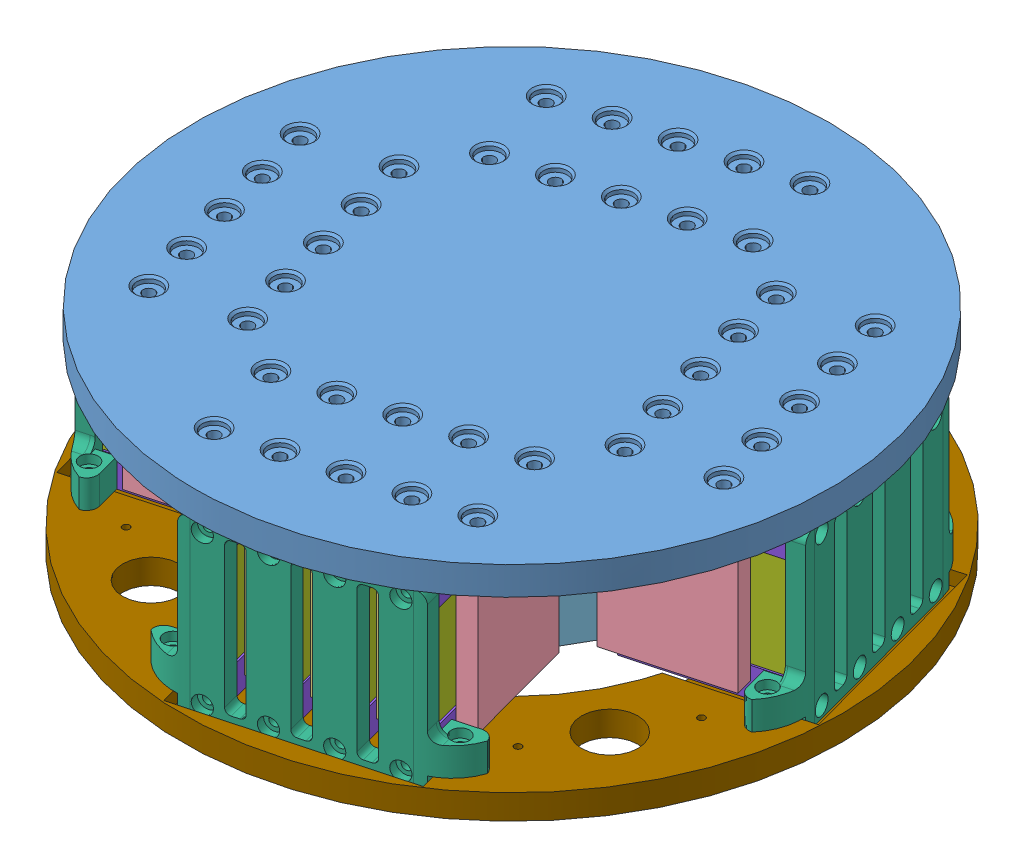
SolidWorks assembly Top_Plate_and_Dampener, configuration Default. Lengths in mm.
Overall size (255.23 60.54 255.23).
80 component instances, 9 part files, 20 mates.
Components (placement in the parent):
- Top_Plate_Test-2: Top_Plate_Test [Default] at (162.7296 -127.7331 -67.6253) size (180 8 180)
- ES-50 supp-2: ES-50 supp [默认] at (103.6666 -172.7331 -107.1936) x (0.965248 0 -0.261336) z (0.261336 0 0.965248) size (75.73 45 71)
- Fin_Long-1: Fin_Long [Default] at (30.3895 -152.9924 -80.4761) x (0 -1 0) z (0.965248 0 -0.261336) size (41.91 5.08 38.1)
- Fin_Long-2: Fin_Long [Default] at (34.3723 -152.9924 -65.7657) x (0 -1 0) z (0.965248 0 -0.261336) size (41.91 5.08 38.1)
- Fin_Long-3: Fin_Long [Default] at (26.4068 -152.9924 -95.1865) x (0 -1 0) z (0.965248 0 -0.261336) size (41.91 5.08 38.1)
- Fin_Short-1: Fin_Short [Default] at (48.3509 -135.5242 -53.7617) x (-0.965248 0 0.261336) z (0 -1 0) size (32.51 5.08 41.91)
- Fin_Long-4: Fin_Long [Default] at (73.9152 -152.9924 -163.5373) x (0 -1 0) z (0.261336 0 0.965248) size (41.91 5.08 38.1)
- Fin_Long-5: Fin_Long [Default] at (156.9764 -152.9924 -120.0117) x (0 -1 0) z (-0.965248 0 0.261336) size (41.91 5.08 38.1)
- Fin_Long-6: Fin_Long [Default] at (113.4508 -152.9924 -36.9505) x (0 -1 0) z (-0.261336 0 -0.965248) size (41.91 5.08 38.1)
- Fin_Long-7: Fin_Long [Default] at (59.2048 -152.9924 -159.5546) x (0 -1 0) z (0.261336 0 0.965248) size (41.91 5.08 38.1)
- Fin_Long-8: Fin_Long [Default] at (152.9937 -152.9924 -134.7221) x (0 -1 0) z (-0.965248 0 0.261336) size (41.91 5.08 38.1)
- Fin_Long-9: Fin_Long [Default] at (128.1612 -152.9924 -40.9332) x (0 -1 0) z (-0.261336 0 -0.965248) size (41.91 5.08 38.1)
- Fin_Long-10: Fin_Long [Default] at (88.6255 -152.9924 -167.5201) x (0 -1 0) z (0.261336 0 0.965248) size (41.91 5.08 38.1)
- Fin_Long-11: Fin_Long [Default] at (160.9592 -152.9924 -105.3013) x (0 -1 0) z (-0.965248 0 0.261336) size (41.91 5.08 38.1)
- Fin_Long-12: Fin_Long [Default] at (98.7404 -152.9924 -32.9677) x (0 -1 0) z (-0.261336 0 -0.965248) size (41.91 5.08 38.1)
- Fin_Short-2: Fin_Short [Default] at (32.4199 -135.5242 -112.6032) x (-0.965248 0 0.261336) z (0 -1 0) size (32.51 5.08 41.91)
- Fin_Short-3: Fin_Short [Default] at (106.0423 -135.5242 -161.507) x (-0.261336 0 -0.965248) z (0 -1 0) size (32.51 5.08 41.91)
- Fin_Short-4: Fin_Short [Default] at (154.946 -135.5242 -87.8846) x (0.965248 0 -0.261336) z (0 -1 0) size (32.51 5.08 41.91)
- Fin_Short-5: Fin_Short [Default] at (81.3237 -135.5242 -38.9808) x (0.261336 0 0.965248) z (0 -1 0) size (32.51 5.08 41.91)
- Fin_Short-6: Fin_Short [Default] at (47.2007 -135.5242 -145.576) x (-0.261336 0 -0.965248) z (0 -1 0) size (32.51 5.08 41.91)
- Fin_Short-7: Fin_Short [Default] at (139.015 -135.5242 -146.7261) x (0.965248 0 -0.261336) z (0 -1 0) size (32.51 5.08 41.91)
- Fin_Short-8: Fin_Short [Default] at (140.1652 -135.5242 -54.9118) x (0.261336 0 0.965248) z (0 -1 0) size (32.51 5.08 41.91)
- Rectangular_Weight-1: Rectangular_Weight [Default] at (112.6132 -169.6431 -99.3448) x (0.261336 0 0.965248) z (-0.965248 0 0.261336) size (75 41.91 75)
- VerticalBraceMagnets-1: VerticalBraceMagnets [Default] at (72.0026 -36.9043 136.8574) x (0.261336 0 0.965248) z (0 -1 0) size (77.76 45.19 49)
  - MagnetBracket_draft4_20160427-1: MagnetBracket_draft4_20160427 [Default] at (-252.0457 -3.1326 136.3687) size (77.76 10 49)
  - BraceMagVertSolid_draft6_20160427-2: BraceMagVertSolid_draft6_20160427 [Default] at (-186.916 -115.49 293.8662) x (0 0 1) z (0 1 0) size (45.4 6.82 42.19)
    - MagnetActual_draf6_20160424-1: MagnetActual_draf6_20160424 [Default] at (-195.3725 -16.2397 114.3575) size (34.75 5.82 40.19)
    - VertMagBraceSolid_draft3_20160427-1: VertMagBraceSolid_draft3_20160427 [Default] at (-155.2965 -9.9197 112.0675) x (0 0 -1) z (0 1 0) size (39.9 45.4 6.82)
  - BraceMagVertSolid_draft6_20160427-3: BraceMagVertSolid_draft6_20160427 [Default] at (-202.216 -115.49 293.8662) x (0 0 1) z (0 1 0) size (45.4 6.82 42.19)
    - MagnetActual_draf6_20160424-1: MagnetActual_draf6_20160424 [Default] at (-195.3725 -16.2397 114.3575) size (34.75 5.82 40.19)
    - VertMagBraceSolid_draft3_20160427-1: VertMagBraceSolid_draft3_20160427 [Default] at (-155.2965 -9.9197 112.0675) x (0 0 -1) z (0 1 0) size (39.9 45.4 6.82)
  - BraceMagVertSolid_draft6_20160427-4: BraceMagVertSolid_draft6_20160427 [Default] at (-217.516 -115.49 293.8662) x (0 0 1) z (0 1 0) size (45.4 6.82 42.19)
    - MagnetActual_draf6_20160424-1: MagnetActual_draf6_20160424 [Default] at (-195.3725 -16.2397 114.3575) size (34.75 5.82 40.19)
    - VertMagBraceSolid_draft3_20160427-1: VertMagBraceSolid_draft3_20160427 [Default] at (-155.2965 -9.9197 112.0675) x (0 0 -1) z (0 1 0) size (39.9 45.4 6.82)
  - BraceMagVertSolid_draft6_20160427-5: BraceMagVertSolid_draft6_20160427 [Default] at (-232.816 -115.49 293.8662) x (0 0 1) z (0 1 0) size (45.4 6.82 42.19)
    - MagnetActual_draf6_20160424-1: MagnetActual_draf6_20160424 [Default] at (-195.3725 -16.2397 114.3575) size (34.75 5.82 40.19)
    - VertMagBraceSolid_draft3_20160427-1: VertMagBraceSolid_draft3_20160427 [Default] at (-155.2965 -9.9197 112.0675) x (0 0 -1) z (0 1 0) size (39.9 45.4 6.82)
- VerticalBraceMagnets-2: VerticalBraceMagnets [Default] at (-143.4184 -36.9043 -121.9243) x (-0.965248 0 0.261336) z (0 -1 0) size (77.76 45.19 49)
  - MagnetBracket_draft4_20160427-1: MagnetBracket_draft4_20160427 [Default] at (-252.0457 -3.1326 136.3687) size (77.76 10 49)
  - BraceMagVertSolid_draft6_20160427-2: BraceMagVertSolid_draft6_20160427 [Default] at (-186.916 -115.49 293.8662) x (0 0 1) z (0 1 0) size (45.4 6.82 42.19)
    - MagnetActual_draf6_20160424-1: MagnetActual_draf6_20160424 [Default] at (-195.3725 -16.2397 114.3575) size (34.75 5.82 40.19)
    - VertMagBraceSolid_draft3_20160427-1: VertMagBraceSolid_draft3_20160427 [Default] at (-155.2965 -9.9197 112.0675) x (0 0 -1) z (0 1 0) size (39.9 45.4 6.82)
  - BraceMagVertSolid_draft6_20160427-3: BraceMagVertSolid_draft6_20160427 [Default] at (-202.216 -115.49 293.8662) x (0 0 1) z (0 1 0) size (45.4 6.82 42.19)
    - MagnetActual_draf6_20160424-1: MagnetActual_draf6_20160424 [Default] at (-195.3725 -16.2397 114.3575) size (34.75 5.82 40.19)
    - VertMagBraceSolid_draft3_20160427-1: VertMagBraceSolid_draft3_20160427 [Default] at (-155.2965 -9.9197 112.0675) x (0 0 -1) z (0 1 0) size (39.9 45.4 6.82)
  - BraceMagVertSolid_draft6_20160427-4: BraceMagVertSolid_draft6_20160427 [Default] at (-217.516 -115.49 293.8662) x (0 0 1) z (0 1 0) size (45.4 6.82 42.19)
    - MagnetActual_draf6_20160424-1: MagnetActual_draf6_20160424 [Default] at (-195.3725 -16.2397 114.3575) size (34.75 5.82 40.19)
    - VertMagBraceSolid_draft3_20160427-1: VertMagBraceSolid_draft3_20160427 [Default] at (-155.2965 -9.9197 112.0675) x (0 0 -1) z (0 1 0) size (39.9 45.4 6.82)
  - BraceMagVertSolid_draft6_20160427-5: BraceMagVertSolid_draft6_20160427 [Default] at (-232.816 -115.49 293.8662) x (0 0 1) z (0 1 0) size (45.4 6.82 42.19)
    - MagnetActual_draf6_20160424-1: MagnetActual_draf6_20160424 [Default] at (-195.3725 -16.2397 114.3575) size (34.75 5.82 40.19)
    - VertMagBraceSolid_draft3_20160427-1: VertMagBraceSolid_draft3_20160427 [Default] at (-155.2965 -9.9197 112.0675) x (0 0 -1) z (0 1 0) size (39.9 45.4 6.82)
- VerticalBraceMagnets-3: VerticalBraceMagnets [Default] at (115.3634 -36.9043 -337.3452) x (-0.261336 0 -0.965248) z (0 -1 0) size (77.76 45.19 49)
  - MagnetBracket_draft4_20160427-1: MagnetBracket_draft4_20160427 [Default] at (-252.0457 -3.1326 136.3687) size (77.76 10 49)
  - BraceMagVertSolid_draft6_20160427-2: BraceMagVertSolid_draft6_20160427 [Default] at (-186.916 -115.49 293.8662) x (0 0 1) z (0 1 0) size (45.4 6.82 42.19)
    - MagnetActual_draf6_20160424-1: MagnetActual_draf6_20160424 [Default] at (-195.3725 -16.2397 114.3575) size (34.75 5.82 40.19)
    - VertMagBraceSolid_draft3_20160427-1: VertMagBraceSolid_draft3_20160427 [Default] at (-155.2965 -9.9197 112.0675) x (0 0 -1) z (0 1 0) size (39.9 45.4 6.82)
  - BraceMagVertSolid_draft6_20160427-3: BraceMagVertSolid_draft6_20160427 [Default] at (-202.216 -115.49 293.8662) x (0 0 1) z (0 1 0) size (45.4 6.82 42.19)
    - MagnetActual_draf6_20160424-1: MagnetActual_draf6_20160424 [Default] at (-195.3725 -16.2397 114.3575) size (34.75 5.82 40.19)
    - VertMagBraceSolid_draft3_20160427-1: VertMagBraceSolid_draft3_20160427 [Default] at (-155.2965 -9.9197 112.0675) x (0 0 -1) z (0 1 0) size (39.9 45.4 6.82)
  - BraceMagVertSolid_draft6_20160427-4: BraceMagVertSolid_draft6_20160427 [Default] at (-217.516 -115.49 293.8662) x (0 0 1) z (0 1 0) size (45.4 6.82 42.19)
    - MagnetActual_draf6_20160424-1: MagnetActual_draf6_20160424 [Default] at (-195.3725 -16.2397 114.3575) size (34.75 5.82 40.19)
    - VertMagBraceSolid_draft3_20160427-1: VertMagBraceSolid_draft3_20160427 [Default] at (-155.2965 -9.9197 112.0675) x (0 0 -1) z (0 1 0) size (39.9 45.4 6.82)
  - BraceMagVertSolid_draft6_20160427-5: BraceMagVertSolid_draft6_20160427 [Default] at (-232.816 -115.49 293.8662) x (0 0 1) z (0 1 0) size (45.4 6.82 42.19)
    - MagnetActual_draf6_20160424-1: MagnetActual_draf6_20160424 [Default] at (-195.3725 -16.2397 114.3575) size (34.75 5.82 40.19)
    - VertMagBraceSolid_draft3_20160427-1: VertMagBraceSolid_draft3_20160427 [Default] at (-155.2965 -9.9197 112.0675) x (0 0 -1) z (0 1 0) size (39.9 45.4 6.82)
- VerticalBraceMagnets-4: VerticalBraceMagnets [Default] at (330.7843 -36.9043 -78.5635) x (0.965248 0 -0.261336) z (0 -1 0) size (77.76 45.19 49)
  - MagnetBracket_draft4_20160427-1: MagnetBracket_draft4_20160427 [Default] at (-252.0457 -3.1326 136.3687) size (77.76 10 49)
  - BraceMagVertSolid_draft6_20160427-2: BraceMagVertSolid_draft6_20160427 [Default] at (-186.916 -115.49 293.8662) x (0 0 1) z (0 1 0) size (45.4 6.82 42.19)
    - MagnetActual_draf6_20160424-1: MagnetActual_draf6_20160424 [Default] at (-195.3725 -16.2397 114.3575) size (34.75 5.82 40.19)
    - VertMagBraceSolid_draft3_20160427-1: VertMagBraceSolid_draft3_20160427 [Default] at (-155.2965 -9.9197 112.0675) x (0 0 -1) z (0 1 0) size (39.9 45.4 6.82)
  - BraceMagVertSolid_draft6_20160427-3: BraceMagVertSolid_draft6_20160427 [Default] at (-202.216 -115.49 293.8662) x (0 0 1) z (0 1 0) size (45.4 6.82 42.19)
    - MagnetActual_draf6_20160424-1: MagnetActual_draf6_20160424 [Default] at (-195.3725 -16.2397 114.3575) size (34.75 5.82 40.19)
    - VertMagBraceSolid_draft3_20160427-1: VertMagBraceSolid_draft3_20160427 [Default] at (-155.2965 -9.9197 112.0675) x (0 0 -1) z (0 1 0) size (39.9 45.4 6.82)
  - BraceMagVertSolid_draft6_20160427-4: BraceMagVertSolid_draft6_20160427 [Default] at (-217.516 -115.49 293.8662) x (0 0 1) z (0 1 0) size (45.4 6.82 42.19)
    - MagnetActual_draf6_20160424-1: MagnetActual_draf6_20160424 [Default] at (-195.3725 -16.2397 114.3575) size (34.75 5.82 40.19)
    - VertMagBraceSolid_draft3_20160427-1: VertMagBraceSolid_draft3_20160427 [Default] at (-155.2965 -9.9197 112.0675) x (0 0 -1) z (0 1 0) size (39.9 45.4 6.82)
  - BraceMagVertSolid_draft6_20160427-5: BraceMagVertSolid_draft6_20160427 [Default] at (-232.816 -115.49 293.8662) x (0 0 1) z (0 1 0) size (45.4 6.82 42.19)
    - MagnetActual_draf6_20160424-1: MagnetActual_draf6_20160424 [Default] at (-195.3725 -16.2397 114.3575) size (34.75 5.82 40.19)
    - VertMagBraceSolid_draft3_20160427-1: VertMagBraceSolid_draft3_20160427 [Default] at (-155.2965 -9.9197 112.0675) x (0 0 -1) z (0 1 0) size (39.9 45.4 6.82)
- Base Plate1 (2)-1: Base Plate1 (2) [默认] at (93.683 -180.2731 -100.2439) x (0.867326 0 0.497741) z (-0.497741 0 0.867326) size (186.97 7 186.97)
Mates (geometry in assembly coordinates):
- Width2: width: plane of ES-50 supp-2 through (70.4644 -127.7331 -65.4675) normal (0.261336 0 0.965248); plane of ES-50 supp-2 through (56.0909 -127.7331 -118.5562) normal (-0.261336 0 -0.965248); axis of Top_Plate_Test-2 through (93.683 -119.7331 -100.2439) axis (0 -1 0)
- Width3: width: plane of ES-50 supp-2 through (56.0909 -127.7331 -118.5562) normal (-0.965248 0 0.261336); plane of ES-50 supp-2 through (116.9016 -127.7331 -135.0203) normal (0.965248 0 -0.261336); axis of Top_Plate_Test-2 through (93.683 -119.7331 -100.2439) axis (0 -1 0)
- Coincident12: coincident anti-aligned: plane of Top_Plate_Test-2 through (93.683 -127.7331 -100.2439) normal (0 -1 0); plane of ES-50 supp-2 through (103.6666 -127.7331 -107.1936) normal (0 1 0)
- Coincident14: coincident anti-aligned: plane of Top_Plate_Test-2 through (93.683 -127.7331 -100.2439) normal (0 -1 0); plane of Fin_Long-1 through (18.9486 -127.7331 -82.6414) normal (0 1 0)
- Parallel3: parallel anti-aligned: plane of ES-50 supp-2 through (54.5105 -132.7331 -99.9982) normal (-0.965248 0 0.261336); plane of Fin_Long-1 through (55.7245 -127.7331 -92.5983) normal (0.965248 0 -0.261336)
- Distance3: distance = 0.762 mm anti-aligned: plane of Fin_Long-1 through (55.7245 -127.7331 -92.5983) normal (0.965248 0 -0.261336); plane of ES-50 supp-2 through (54.5105 -132.7331 -99.9982) normal (-0.965248 0 0.261336)
- Width4: width aligned: plane of Fin_Long-1 through (30.3895 -152.9924 -80.4761) normal (0.261336 0 0.965248); plane of Fin_Long-1 through (29.0619 -152.9924 -85.3796) normal (-0.261336 0 -0.965248); plane of ES-50 supp-2 through (70.4644 -127.7331 -65.4675) normal (0.261336 0 0.965248); plane of ES-50 supp-2 through (56.0909 -127.7331 -118.5562) normal (-0.261336 0 -0.965248)
- Coincident20: coincident anti-aligned: plane of Top_Plate_Test-2 through (93.683 -127.7331 -100.2439) normal (0 -1 0); plane of Fin_Short-1 through (63.69 -127.7331 -63.1775) normal (0 1 0)
- Parallel9: parallel anti-aligned: plane of ES-50 supp-2 through (54.5105 -132.7331 -99.9982) normal (-0.965248 0 0.261336); plane of Fin_Short-1 through (63.69 -127.7331 -63.1775) normal (0.965248 0 -0.261336)
- Distance5: distance = 0.762 mm anti-aligned: plane of Fin_Short-1 through (63.69 -127.7331 -63.1775) normal (0.965248 0 -0.261336); plane of ES-50 supp-2 through (54.5105 -132.7331 -99.9982) normal (-0.965248 0 0.261336)
- Distance6: distance = 10.16 mm anti-aligned: plane of Fin_Long-2 through (34.3723 -152.9924 -65.7657) normal (0.261336 0 0.965248); plane of Fin_Short-1 through (47.0233 -135.5242 -58.6651) normal (-0.261336 0 -0.965248)
- Width5: width anti-aligned: plane of Rectangular_Weight-1 through (139.6799 -127.7331 -73.8472) normal (0.261336 0 0.965248); plane of Rectangular_Weight-1 through (120.0797 -127.7331 -146.2408) normal (-0.261336 0 -0.965248); plane of ES-50 supp-2 through (56.0909 -127.7331 -118.5562) normal (-0.261336 0 -0.965248); plane of ES-50 supp-2 through (70.4644 -127.7331 -65.4675) normal (0.261336 0 0.965248)
- Width6: width aligned: plane of Rectangular_Weight-1 through (54.8643 -127.7331 -119.2601) normal (0.965248 0 -0.261336); plane of Rectangular_Weight-1 through (117.6055 -127.7331 -136.2469) normal (-0.965248 0 0.261336); plane of ES-50 supp-2 through (116.9016 -127.7331 -135.0203) normal (0.965248 0 -0.261336); plane of ES-50 supp-2 through (56.0909 -127.7331 -118.5562) normal (-0.965248 0 0.261336)
- Coincident29: coincident anti-aligned: plane of Top_Plate_Test-2 through (93.683 -127.7331 -100.2439) normal (0 -1 0); plane of Rectangular_Weight-1 through (112.6132 -127.7331 -99.3448) normal (0 1 0)
- Width8: width anti-aligned: plane of VerticalBraceMagnets-1/BraceMagVertSolid_draft6_20160427-5/MagnetActual_draf6_20160424-1 through (8.0087 -135.3981 -103.8391) normal (-0.261336 0 -0.965248); plane of VerticalBraceMagnets-1/BraceMagVertSolid_draft6_20160427-2/MagnetActual_draf6_20160424-1 through (21.5249 -135.3981 -53.9165) normal (0.261336 0 0.965248); plane of Fin_Short-1 through (48.3509 -135.5242 -53.7617) normal (0.261336 0 0.965248); plane of Fin_Short-2 through (31.0923 -135.5242 -117.5066) normal (-0.261336 0 -0.965248)
- Distance7: distance = 3.02 mm anti-aligned: plane of Fin_Long-3 through (14.9658 -127.7331 -97.3518) normal (-0.965248 0 0.261336); plane of VerticalBraceMagnets-1/MagnetBracket_draft4_20160427-1 through (9.1578 -173.2731 -107.2479) normal (0.965248 0 -0.261336)
- Distance11: distance = 0.54 mm anti-aligned: plane of VerticalBraceMagnets-1/MagnetBracket_draft4_20160427-1 through (9.1578 -128.2731 -107.2479) normal (0 1 0); plane of Top_Plate_Test-2 through (93.683 -127.7331 -100.2439) normal (0 -1 0)
- Concentric2: concentric anti-aligned: cylinder of Top_Plate_Test-2 through (93.683 -119.7331 -100.2439) axis (0 -1 0) radius 90; cylinder of Base Plate1 (2)-1 through (93.683 -180.2731 -100.2439) axis (0 1 0) radius 60
- Coincident32: coincident anti-aligned: plane of VerticalBraceMagnets-3/MagnetBracket_draft4_20160427-1 through (183.0344 -173.2731 -94.5466) normal (0 -1 0); plane of Base Plate1 (2)-1 through (93.683 -173.2731 -100.2439) normal (0 1 0)
- Parallel11: parallel anti-aligned: plane of VerticalBraceMagnets-3/MagnetBracket_draft4_20160427-1 through (183.0344 -173.2731 -94.5466) normal (0.965248 0 -0.261336); plane of Base Plate1 (2)-1 through (178.6685 -177.2731 -123.2533) normal (-0.965248 0 0.261336)
